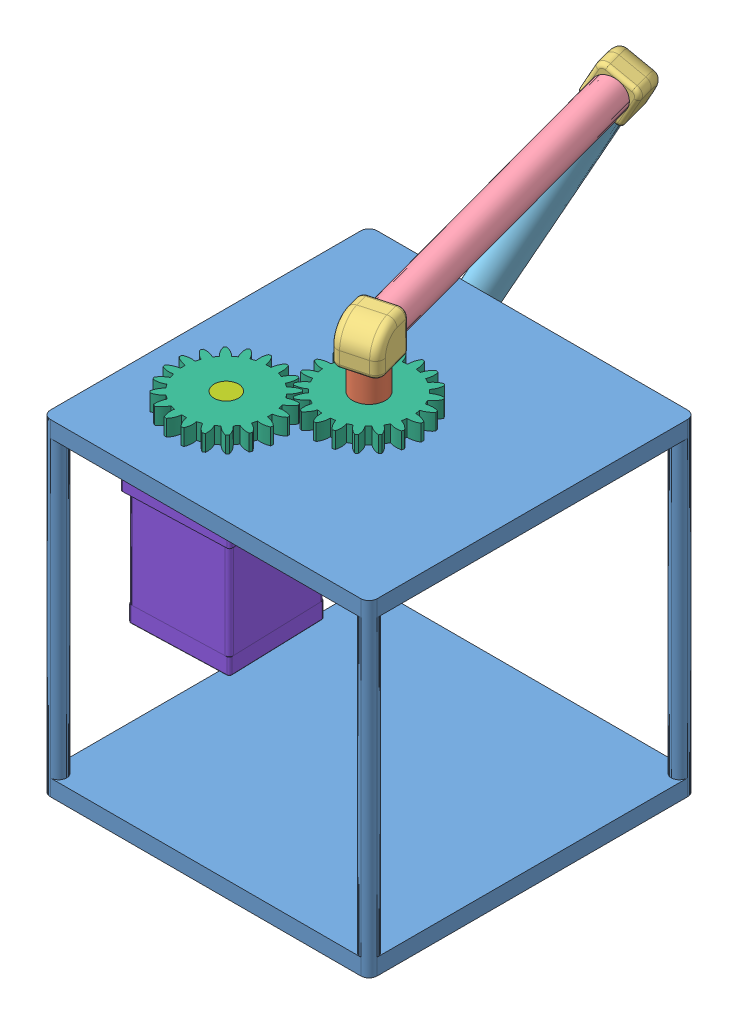
SolidWorks assembly Assem4, configuration Default. Lengths in mm.
Overall size (568.54 516.71 660.54).
10 component instances, 8 part files, 25 mates.
Components (placement in the parent):
- body-1: body [Default] at (152.1901 30.957 290.4214) size (400 400 400)
- mile1-1: mile1 [Default] at (152.1901 410.957 290.4214) x (-0.487718 0 -0.873001) z (0.873001 0 -0.487718) size (40 80 40)
- conector1-1: conector1 [Default] at (152.1901 488.957 290.4214) x (0.965217 0 -0.261451) z (0.261451 0 0.965217) size (50 50 50)
- mile2-2: mile2 [Default] at (146.9611 513.957 271.1171) x (-0.000753 1 0.000204) z (-0.965216 -0.00078 0.261451) size (40 400 40)
- conector1-2: conector1 [Default] at (42.9035 513.957 -113.0391) x (0.856384 -0.461298 -0.231971) z (0.445253 0.887245 -0.120607) size (50 50 50)
- mile3-1: mile3 [Default] at (27.4622 496.2121 -134.7574) x (-0.876604 0.404475 -0.260701) z (-0.182523 0.221802 0.957856) size (40 500 40)
- spur gear_iso-1: spur gear_iso [ISO - Spur gear 6M 20T 20PA 20FW ---S20A75H50L40.0N] at (152.1901 455.957 290.4214) x (0 -1 0) z (0.701388 0 0.71278) size (20 130.83 130.83)
- spur gear_iso-2: spur gear_iso [ISO - Spur gear 6M 20T 20PA 20FW ---S20A75H50L30.0N] at (64.8624 455.957 377.7491) x (0 -1 0) z (0.800284 0 -0.599621) size (20 130.83 130.83)
- mile_motor-1: mile_motor [Default] at (64.8624 395.957 377.7491) x (0.850661 0 -0.525714) z (0.525714 0 0.850661) size (30 60 30)
- DCMOTORRR-1: DCMOTORRR [3] at (64.8624 352.957 377.7491) x (-0.032001 0 -0.999488) z (0 1 0) size (130 135 183)
Mates (geometry in assembly coordinates):
- Concentric1: concentric: cylinder of body-1 through (152.1901 410.957 290.4214) axis (0 1 0) radius 20; cylinder of mile1-1 through (152.1901 490.957 290.4214) axis (0 -1 0) radius 20
- Concentric4: concentric: cylinder of mile1-1 through (152.1901 490.957 290.4214) axis (0 -1 0) radius 20; cylinder of conector1-1 through (152.1901 490.957 290.4214) axis (0 -1 0) radius 20
- Coincident3: coincident: plane of mile1-1 through (152.1901 490.957 290.4214) normal (0 1 0); plane of conector1-1 through (152.1901 490.957 290.4214) normal (0 -1 0)
- Concentric7: concentric: cylinder of conector1-1 through (146.9611 513.957 271.1171) axis (-0.261451 0 -0.965217) radius 20; cylinder of mile2-2 through (42.3806 513.957 -114.9696) axis (0.261451 0 0.965217) radius 20
- Concentric8: concentric: cylinder of conector1-1 through (146.9611 513.957 271.1171) axis (-0.261451 0 -0.965217) radius 20; cylinder of mile2-2 through (42.3806 513.957 -114.9696) axis (0.261451 0 0.965217) radius 20
- Coincident4: coincident: plane of conector1-1 through (146.9611 513.957 271.1171) normal (-0.261451 0 -0.965217); plane of mile2-2 through (146.9611 513.957 271.1171) normal (0.261451 0 0.965217)
- Concentric10: concentric: circle of mile2-2; circle of conector1-2
- Concentric11: concentric: circle of mile2-2; circle of conector1-2
- Coincident8: coincident: plane of mile2-2 through (42.3806 513.957 -114.9696) normal (-0.261451 0 -0.965217); plane of conector1-2 through (42.3806 513.957 -114.9696) normal (0.261451 0 0.965217)
- Concentric12: concentric: cylinder of conector1-2 through (27.4622 496.2121 -134.7574) axis (-0.445253 -0.887245 0.120607) radius 20; cylinder of mile3-1 through (-195.1642 52.5895 -74.4539) axis (0.445253 0.887245 -0.120607) radius 20
- Coincident9: coincident: plane of conector1-2 through (27.4622 496.2121 -134.7574) normal (-0.445253 -0.887245 0.120607); plane of mile3-1 through (27.4622 496.2121 -134.7574) normal (0.445253 0.887245 -0.120607)
- Concentric13: concentric: cylinder of mile1-1 through (152.1901 490.957 290.4214) axis (0 -1 0) radius 20; cylinder of spur gear_iso-1 through (152.1901 405.9569 290.4214) axis (0 1 0) radius 20
- Concentric15: concentric: cylinder of body-1 through (64.8624 359.957 377.7491) axis (0 1 0) radius 15; cylinder of spur gear_iso-2 through (64.8624 405.9569 377.7491) axis (0 1 0) radius 15
- Concentric17: concentric: cylinder of mile1-1 through (152.1901 490.957 290.4214) axis (0 -1 0) radius 20; cylinder of spur gear_iso-1 through (152.1901 405.9569 290.4214) axis (0 1 0) radius 20
- Coincident12: coincident: plane of body-1 through (332.1901 410.957 90.4214) normal (0 -1 0); plane of mile1-1 through (152.1901 410.957 290.4214) normal (0 -1 0)
- Concentric18: concentric: cylinder of spur gear_iso-2 through (64.8624 405.9569 377.7491) axis (0 1 0) radius 15; cylinder of mile_motor-1 through (64.8624 455.957 377.7491) axis (0 -1 0) radius 15
- Concentric19: concentric: cylinder of spur gear_iso-2 through (64.8624 405.9569 377.7491) axis (0 1 0) radius 15; cylinder of mile_motor-1 through (64.8624 455.957 377.7491) axis (0 -1 0) radius 15
- Coincident14: coincident: plane of spur gear_iso-2 through (64.8624 455.957 377.7491) normal (0 1 0); plane of mile_motor-1 through (64.8624 455.957 377.7491) normal (0 1 0)
- Distance1: distance = 15 mm: plane of body-1 through (332.1901 410.957 90.4214) normal (0 -1 0); plane of mile_motor-1 through (64.8624 395.957 377.7491) normal (0 -1 0)
- GearMate4: gear = 40 : 40 mm: cylinder of spur gear_iso-1 through (152.1901 405.9569 290.4214) axis (0 1 0) radius 20; cylinder of spur gear_iso-2 through (64.8624 405.9569 377.7491) axis (0 1 0) radius 15
- Lock1: lock: unknown of mile1-1; unknown of conector1-1
- Coincident19: coincident: plane of mile_motor-1 through (64.8624 395.957 377.7491) normal (0 -1 0); plane of DCMOTORRR-1 through (64.8624 395.957 377.7491) normal (0 1 0)
- Concentric20: concentric: cylinder of mile_motor-1 through (64.8624 455.957 377.7491) axis (0 -1 0) radius 15; cylinder of DCMOTORRR-1 through (64.8624 395.957 377.7491) axis (0 -1 0) radius 15
- Lock2: lock: unknown of mile1-1; unknown of spur gear_iso-1
- Lock3: lock: unknown of spur gear_iso-2; unknown of mile_motor-1
